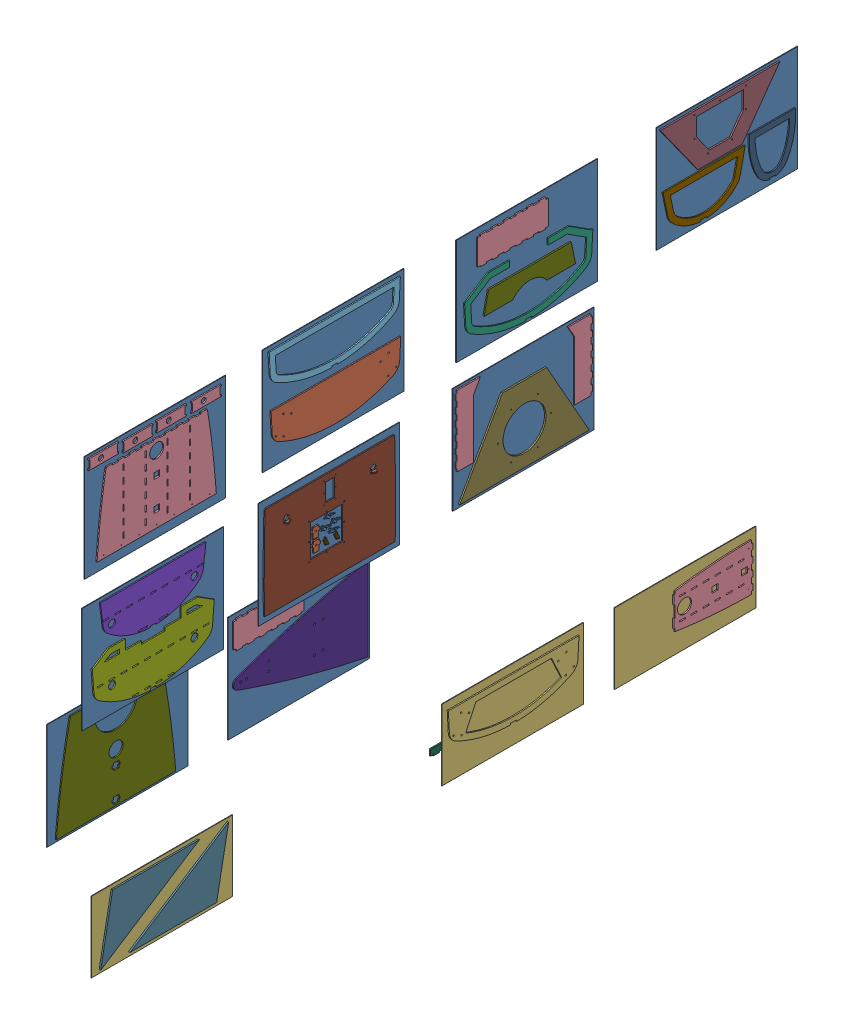
SolidWorks assembly Sheet1, configuration Default. Lengths in mm.
Overall size (328.79 2588.57 3186.12).
47 component instances, 22 part files, 50 mates.
Components (placement in the parent):
- 18x24_Stock-1: 18x24_Stock [Default] at origin size (2.54 457.2 609.6)
- Transom-1: Transom [Default] at (7.62 1.4933 -775.0627) x (0 0 1) z (-1 0 0) size (559.11 184.29 5.09)
- RudderForward-1: RudderForward [Default] at (203.3436 -1395.0051 -1437.0934) x (0 0 1) z (-1 0 0) size (563.45 186.42 6.36)
- RudderTubeStabilizer-1: RudderTubeStabilizer [Default] at (7.62 186.5439 78.437) x (0 0 -1) z (0 1 0) size (128.91 5.08 44.45)
- RudderTubeStabilizer-2: RudderTubeStabilizer [Default] at (7.62 194.7513 226.2554) x (0 0 -1) z (0 1 0) size (128.91 5.08 44.45)
- RudderTubeStabilizer-3: RudderTubeStabilizer [Default] at (7.62 189.0224 -65.5947) x (0 0 -1) z (0 1 0) size (128.91 5.08 44.45)
- RudderTubeStabilizer-4: RudderTubeStabilizer [Default] at (7.62 187.0824 -216.3971) x (0 0 -1) z (0 1 0) size (128.91 5.08 44.45)
- 18x24_Stock-2: 18x24_Stock [Default] at (0 14.1456 -768.1416) size (2.54 457.2 609.6)
- 18x24_Stock-3: 18x24_Stock [Default] at (0 -561.0027 9.0978) size (2.54 457.2 609.6)
- 18x24_Stock-4: 18x24_Stock [Default] at (0 -550.3057 -750.3876) size (2.54 457.2 609.6)
- 18x24_Stock-5: 18x24_Stock [Default] at (0 7.1673 -1604.1133) size (2.54 457.2 609.6)
- 18x24_Stock-6: 18x24_Stock [Default] at (0 -539.6622 -1588.7097) size (2.54 457.2 609.6)
- 18x24_Stock-7: 18x24_Stock [Default] at (0 -4.3855 -2466.7176) size (2.54 457.2 609.6)
- Rib 2-2: Rib 2 [Default] at (326.39 226.3847 -769.9956) x (0 0 1) z (-1 0 0) size (565.69 192.06 6.36)
- Rib 3-2: Rib 3 [Default] at (586.74 -11.3845 -1606.4845) x (0 0 1) z (-1 0 0) size (553.21 260.44 6.36)
- Rib 4-2: Rib 4 [Default] at (835.66 -576.6079 12.7093) x (0 0 1) z (-1 0 0) size (526.23 245.9 5.09)
- Rib 6-2: Rib 6 [Default] at (1170.94 -346.3352 12.8856) x (0 0 1) z (-1 0 0) size (455.12 199.45 5.09)
- Rib 7-1: Rib 7 [Default] at (1440.815 -27.1717 -2362.7522) x (0 0 1) z (-1 0 0) size (353.94 188.86 6.36)
- Rib 8-1: Rib 8 [Default] at (1729.74 -38.5662 -2657.4361) x (0 0 1) z (-1 0 0) size (199.86 211.4 6.36)
- BallJointLinkageRudderDeck-1: BallJointLinkageRudderDeck [Default] at (2.54 -351.9252 -748.8179) x (0 0 -1) z (0 -1 0) size (590.36 222.07 2004.6)
- AngledBallast_DeckBack-1: AngledBallast_DeckBack [Default] at (2.54 -753.0301 -1307.5301) size (6.35 325.69 558.8)
- AngledBallast_DeckFront-1: AngledBallast_DeckFront [Default] at (8.89 212.0487 -2430.4018) x (-1 0 0) z (0 0 1) size (6.35 227.24 515.62)
- AngledBallast_DeckSides-1: AngledBallast_DeckSides [Default] at (66.4488 -1375.3072 -247.3734) x (1 0 0) z (0 0.541803 -0.840505) size (6.35 202.67 506.73)
- AngledBallast_DeckSides-2: AngledBallast_DeckSides [Default] at (66.4488 -1653.1024 304.795) x (1 0 0) z (0 -0.541803 0.840505) size (6.35 202.67 506.73)
- MastToKeelShelf-1: MastToKeelShelf [Default] at (7.62 -1617.3141 -1436.6558) x (0 0 1) z (0 -1 0) size (508 5.08 30.48)
- Deck Tapered Riser-1: Deck Tapered Riser [Spacer Deck] at (2.54 -798.0944 -1619.0492) x (0 0 1) z (0 1 0) size (394.27 5.1 90.63)
- Deck Tapered Riser-2: Deck Tapered Riser [Mast Deck] at (-141.1937 -1542.7815 21.6008) x (0 0 1) z (0 1 0) size (514.69 5.1 431.82)
- 18x24_Stock-9: 18x24_Stock [Default] at (-143.7337 -1063.3496 17.9645) size (2.54 457.2 609.6)
- 18x24_Stock-10: 18x24_Stock [Default] at (-146.1919 -1056.1557 -766.5111) size (2.54 457.2 609.6)
- Foredeck-1: Foredeck [Default] at (-143.6519 -1083.3842 -1836.8729) x (0 -1 0) z (0 0 1) size (357.98 5.08 579.69)
- AboveDeckKeelBoxBack-1: AboveDeckKeelBoxBack [Default] at (7.62 -605.4407 -779.3959) x (-1 0 0) z (0 -0.924225 -0.381849) size (5.08 12.19 34.29)
- AboveDeckKeelBoxSide-1: AboveDeckKeelBoxSide [Default] at (7.62 -517.8456 -759.6315) x (0 0 1) z (-1 0 0) size (47.21 20.25 5.08)
- AboveDeckKeelBoxTop-1: AboveDeckKeelBoxTop [Default] at (2.54 -592.0193 -690.7339) x (0 -1 0) z (0 0 1) size (44.38 5.08 34.29)
- AboveDeckKeelBoxSide-2: AboveDeckKeelBoxSide [Default] at (7.62 -554.2797 -743.5995) x (0 0 1) z (-1 0 0) size (47.21 20.25 5.08)
- AboveDeckKeelBoxSide-3: AboveDeckKeelBoxSide [Default] at (7.62 -579.3656 -777.1087) x (0 0 1) z (-1 0 0) size (47.21 20.25 5.08)
- AboveDeckKeelBoxTop-2: AboveDeckKeelBoxTop [Default] at (2.54 -539.0149 -688.3381) x (0 -1 0) z (0 0 1) size (44.38 5.08 34.29)
- AboveDeckKeelBoxSide-4: AboveDeckKeelBoxSide [Default] at (7.62 -548.6048 -788.0505) x (0 0 1) z (-1 0 0) size (47.21 20.25 5.08)
- AboveDeckKeelBoxBack-2: AboveDeckKeelBoxBack [Default] at (7.62 -603.8251 -732.8834) x (-1 0 0) z (0 -0.924225 -0.381849) size (5.08 12.19 34.29)
- 12x24_Stock-1: 12x24_Stock [Default] at (63.9088 -1515.72 33.6095) size (2.54 304.8 609.6)
- 12x24_Stock-3: 12x24_Stock [Default] at (104.4106 -1513.9325 -1437.7801) size (2.54 304.8 609.6)
- 12x24_Stock-4: 12x24_Stock [Default] at (120.4962 -1509.9115 -2165.5427) size (2.54 304.8 609.6)
- MastToKeelPlates-1: MastToKeelPlates [Vertical] at (-94.1219 -1035.6732 372.7319) x (1 0 0) z (0 0 -1) size (5.08 119.38 304.8)
- MastToKeelPlates-2: MastToKeelPlates [Vertical] at (52.07 280.8254 -2542.8286) size (5.08 119.38 304.8)
- MastToKeelPlates-3: MastToKeelPlates [Top] at (-68.58 -1020.1227 -2.0768) x (0 0 -1) z (0 1 0) size (514.31 5.09 335.29)
- MastToKeelPlates-4: MastToKeelPlates [Bottom] at (-62.3838 -1496.091 -3280.036) x (0 1 0) z (0 0 1) size (202.63 5.09 340.36)
- MastToKeelPlates-5: MastToKeelPlates [TopVertical] at (-138.43 527.9016 -1804.8169) x (1 0 0) z (0 -1 0) size (5.08 104.78 304.8)
- MastToKeelPlates-6: MastToKeelPlates [TopVertical] at (148.59 530.9594 -1369.0811) x (-1 0 0) z (0 -1 0) size (5.08 104.78 304.8)
Mates (geometry in assembly coordinates):
- Coincident1: coincident anti-aligned: plane of 12x24_Stock-3 through (106.9506 -1513.9325 -1437.7801) normal (1 0 0); plane of RudderForward-1 through (106.9506 -1547.0885 -1631.8479) normal (-1 0 0)
- Coincident3: coincident anti-aligned: plane of 18x24_Stock-1 through (2.54 0 0) normal (1 0 0); plane of RudderTubeStabilizer-1 through (2.54 186.5439 78.437) normal (-1 0 0)
- Coincident4: coincident anti-aligned: plane of 18x24_Stock-1 through (2.54 0 0) normal (1 0 0); plane of RudderTubeStabilizer-3 through (2.54 189.0224 -65.5947) normal (-1 0 0)
- Coincident5: coincident anti-aligned: plane of 18x24_Stock-1 through (2.54 0 0) normal (1 0 0); plane of RudderTubeStabilizer-2 through (2.54 194.7513 226.2554) normal (-1 0 0)
- Coincident6: coincident anti-aligned: plane of 18x24_Stock-1 through (2.54 0 0) normal (1 0 0); plane of RudderTubeStabilizer-4 through (2.54 187.0824 -216.3971) normal (-1 0 0)
- Parallel1: parallel anti-aligned: line of 18x24_Stock-1 through (2.54 228.6 -304.8) axis (0 0 1); line of RudderTubeStabilizer-2 through (7.62 172.5263 290.7079) axis (0 0 -1)
- Parallel2: parallel anti-aligned: line of 18x24_Stock-1 through (2.54 228.6 -304.8) axis (0 0 1); line of RudderTubeStabilizer-1 through (7.62 164.3189 142.8895) axis (0 0 -1)
- Parallel3: parallel anti-aligned: line of 18x24_Stock-1 through (2.54 228.6 -304.8) axis (0 0 1); line of RudderTubeStabilizer-3 through (7.62 166.7974 -1.1422) axis (0 0 -1)
- Parallel4: parallel anti-aligned: line of 18x24_Stock-1 through (2.54 228.6 -304.8) axis (0 0 1); line of RudderTubeStabilizer-4 through (7.62 164.8574 -151.9446) axis (0 0 -1)
- Coincident13: coincident anti-aligned: plane of 18x24_Stock-2 through (2.54 14.1456 -768.1416) normal (1 0 0); plane of Rib 2-2 through (2.54 71.4923 -965.4264) normal (-1 0 0)
- Coincident15: coincident anti-aligned: plane of 18x24_Stock-5 through (2.54 7.1673 -1604.1133) normal (1 0 0); plane of Rib 3-2 through (2.54 -170.1642 -1797.7928) normal (-1 0 0)
- Coincident17: coincident anti-aligned: plane of 18x24_Stock-7 through (2.54 -4.3855 -2466.7176) normal (1 0 0); plane of Rib 6-2 through (2.54 -498.3408 -152.0272) normal (-1 0 0)
- Coincident18: coincident anti-aligned: plane of 18x24_Stock-7 through (2.54 -4.3855 -2466.7176) normal (1 0 0); plane of Rib 8-1 through (2.54 -38.5662 -2657.4361) normal (-1 0 0)
- Coincident19: coincident anti-aligned: plane of 18x24_Stock-7 through (2.54 -4.3855 -2466.7176) normal (1 0 0); plane of Rib 7-1 through (2.54 -164.3321 -2496.077) normal (-1 0 0)
- Coincident20: coincident anti-aligned: plane of 18x24_Stock-3 through (2.54 -561.0027 9.0978) normal (1 0 0); plane of Rib 4-2 through (2.54 -736.0565 -172.8403) normal (-1 0 0)
- Coincident21: coincident anti-aligned: plane of 18x24_Stock-4 through (2.54 -550.3057 -750.3876) normal (1 0 0); plane of BallJointLinkageRudderDeck-1 through (2.54 -554.4349 -1031.8204) normal (-1 0 0)
- Parallel5: parallel anti-aligned: line of 18x24_Stock-4 through (2.54 -778.9057 -445.5876) axis (0 0 -1); line of BallJointLinkageRudderDeck-1 through (7.62 -351.9252 -1023.2784) axis (0 0 1)
- Coincident27: coincident anti-aligned: plane of 18x24_Stock-6 through (2.54 -539.6622 -1588.7097) normal (1 0 0); plane of AngledBallast_DeckBack-1 through (2.54 -753.0301 -1307.5301) normal (-1 0 0)
- Coincident29: coincident anti-aligned: plane of 18x24_Stock-4 through (2.54 -550.3057 -750.3876) normal (1 0 0); plane of MastToKeelShelf-1 through (2.54 -1617.3141 -1436.6558) normal (-1 0 0)
- Parallel8: parallel anti-aligned: line of 18x24_Stock-4 through (2.54 -778.9057 -445.5876) axis (0 0 -1); line of MastToKeelShelf-1 through (7.62 -1604.6141 -1690.6558) axis (0 0 1)
- Coincident31: coincident anti-aligned: plane of 18x24_Stock-5 through (2.54 7.1673 -1604.1133) normal (1 0 0); plane of Deck Tapered Riser-1 through (2.54 545.852 -1605.9633) normal (-1 0 0)
- Parallel9: parallel anti-aligned: line of 18x24_Stock-5 through (2.54 235.7673 -1908.9133) axis (0 0 1); line of Deck Tapered Riser-1 through (7.62 -13.504 -1433.1555) axis (0 0 -1)
- Coincident33: coincident anti-aligned: plane of Deck Tapered Riser-2 through (-141.1937 -198.8351 34.6868) normal (-1 0 0); plane of 18x24_Stock-9 through (-141.1937 -1063.3496 17.9645) normal (1 0 0)
- Parallel10: parallel anti-aligned: line of Deck Tapered Riser-2 through (-136.1137 -1279.8521 -228.0171) axis (0 0 1); line of 18x24_Stock-9 through (-141.1937 -1291.9496 322.7645) axis (0 0 -1)
- Coincident35: coincident anti-aligned: plane of 18x24_Stock-10 through (-143.6519 -1056.1557 -766.5111) normal (1 0 0); plane of Foredeck-1 through (-143.6519 -980.49 -772.6931) normal (-1 0 0)
- Parallel11: parallel aligned: line of 18x24_Stock-10 through (-143.6519 -1284.7557 -1071.3111) axis (0 1 0); line of Foredeck-1 through (-138.5719 -1270.0904 -1058.7706) axis (0 1 0)
- Coincident37: coincident anti-aligned: plane of 18x24_Stock-4 through (2.54 -550.3057 -750.3876) normal (1 0 0); plane of AboveDeckKeelBoxBack-2 through (2.54 -603.8251 -732.8834) normal (-1 0 0)
- Coincident38: coincident anti-aligned: plane of 18x24_Stock-4 through (2.54 -550.3057 -750.3876) normal (1 0 0); plane of AboveDeckKeelBoxBack-1 through (2.54 -605.4407 -779.3959) normal (-1 0 0)
- Coincident39: coincident anti-aligned: plane of 18x24_Stock-4 through (2.54 -550.3057 -750.3876) normal (1 0 0); plane of AboveDeckKeelBoxSide-3 through (2.54 -579.3656 -777.1087) normal (-1 0 0)
- Coincident40: coincident anti-aligned: plane of 18x24_Stock-4 through (2.54 -550.3057 -750.3876) normal (1 0 0); plane of AboveDeckKeelBoxSide-2 through (2.54 -554.2797 -743.5995) normal (-1 0 0)
- Coincident41: coincident anti-aligned: plane of 18x24_Stock-4 through (2.54 -550.3057 -750.3876) normal (1 0 0); plane of AboveDeckKeelBoxSide-1 through (2.54 -517.8456 -759.6315) normal (-1 0 0)
- Coincident42: coincident anti-aligned: plane of 18x24_Stock-4 through (2.54 -550.3057 -750.3876) normal (1 0 0); plane of AboveDeckKeelBoxTop-1 through (2.54 -592.0193 -690.7339) normal (-1 0 0)
- Coincident43: coincident anti-aligned: plane of 18x24_Stock-4 through (2.54 -550.3057 -750.3876) normal (1 0 0); plane of AboveDeckKeelBoxSide-4 through (2.54 -548.6048 -788.0505) normal (-1 0 0)
- Coincident44: coincident anti-aligned: plane of 18x24_Stock-4 through (2.54 -550.3057 -750.3876) normal (1 0 0); plane of AboveDeckKeelBoxTop-2 through (2.54 -539.0149 -688.3381) normal (-1 0 0)
- Coincident46: coincident anti-aligned: plane of AngledBallast_DeckSides-2 through (66.4488 -1653.1024 304.795) normal (-1 0 0); plane of 12x24_Stock-1 through (66.4488 -1515.72 33.6095) normal (1 0 0)
- Coincident48: coincident anti-aligned: plane of AngledBallast_DeckSides-1 through (66.4488 -1375.3072 -247.3734) normal (-1 0 0); plane of 12x24_Stock-1 through (66.4488 -1515.72 33.6095) normal (1 0 0)
- Parallel14: parallel aligned: line of AngledBallast_DeckSides-2 through (72.7988 -1378.5546 -121.1143) axis (0 0 1); line of 12x24_Stock-1 through (66.4488 -1363.32 -271.1905) axis (0 0 1)
- Parallel15: parallel aligned: line of AngledBallast_DeckSides-1 through (72.7988 -1649.8551 178.5359) axis (0 0 -1); line of 12x24_Stock-1 through (66.4488 -1668.12 338.4095) axis (0 0 -1)
- Coincident53: coincident anti-aligned: plane of 18x24_Stock-1 through (2.54 0 0) normal (1 0 0); plane of MastToKeelPlates-3 through (2.54 -1020.1227 -2.0768) normal (-1 0 0)
- Parallel17: parallel aligned: line of 18x24_Stock-1 through (2.54 -228.6 304.8) axis (0 0 -1); line of MastToKeelPlates-3 through (7.62 -187.0027 255.0733) axis (0 0 -1)
- Coincident55: coincident anti-aligned: plane of 12x24_Stock-4 through (123.0362 -1509.9115 -2165.5427) normal (1 0 0); plane of MastToKeelPlates-4 through (123.0362 -1394.7801 -2446.8129) normal (-1 0 0)
- Parallel20: parallel anti-aligned: line of 18x24_Stock-10 through (-143.6519 -827.5557 -461.7111) axis (0 -1 0); line of MastToKeelPlates-1 through (-143.6519 -954.3932 -479.4381) axis (0 1 0)
- Coincident61: coincident anti-aligned: plane of 18x24_Stock-10 through (-143.6519 -1056.1557 -766.5111) normal (1 0 0); plane of MastToKeelPlates-1 through (-143.6519 -1035.6732 372.7319) normal (-1 0 0)
- Coincident62: coincident anti-aligned: plane of 18x24_Stock-5 through (2.54 7.1673 -1604.1133) normal (1 0 0); plane of MastToKeelPlates-2 through (2.54 280.8254 -2542.8286) normal (-1 0 0)
- Parallel21: parallel aligned: line of 18x24_Stock-5 through (2.54 235.7673 -1299.3133) axis (0 -1 0); line of MastToKeelPlates-2 through (7.62 204.6254 -1385.8586) axis (0 -1 0)
- Coincident64: coincident anti-aligned: plane of Transom-1 through (2.54 -149.5196 -968.8071) normal (-1 0 0); plane of 18x24_Stock-2 through (2.54 14.1456 -768.1416) normal (1 0 0)
- Parallel23: parallel aligned: line of 18x24_Stock-6 through (2.54 -768.2622 -1893.5097) axis (0 1 0); line of MastToKeelPlates-5 through (7.62 -629.0684 -1804.8169) axis (0 1 0)
- Coincident67: coincident anti-aligned: plane of 18x24_Stock-6 through (2.54 -539.6622 -1588.7097) normal (1 0 0); plane of MastToKeelPlates-5 through (2.54 527.9016 -1804.8169) normal (-1 0 0)
- Coincident68: coincident anti-aligned: plane of 18x24_Stock-6 through (2.54 -539.6622 -1588.7097) normal (1 0 0); plane of MastToKeelPlates-6 through (2.54 530.9594 -1369.0811) normal (-1 0 0)
- Parallel24: parallel anti-aligned: line of 18x24_Stock-6 through (2.54 -311.0622 -1283.9097) axis (0 -1 0); line of MastToKeelPlates-6 through (7.62 -626.0106 -1369.0811) axis (0 1 0)
